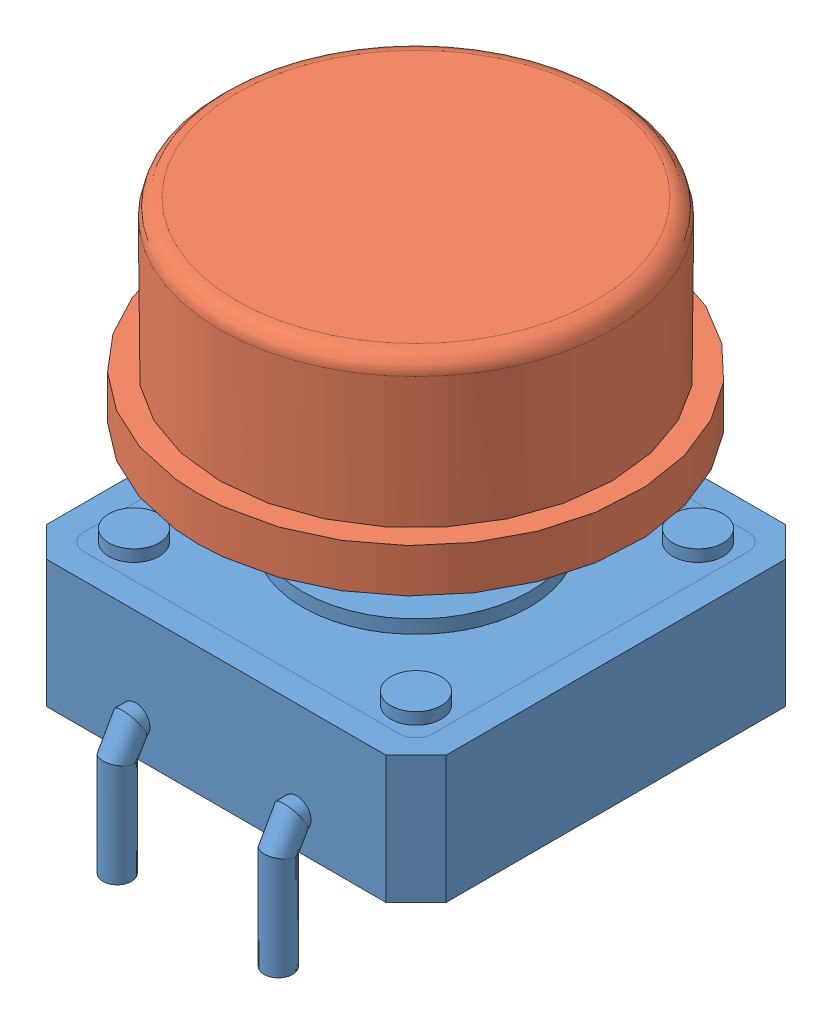
SolidWorks assembly Кнопка с колпачком, configuration По умолчанию. Lengths in mm.
Overall size (13 15.4 13.85).
2 component instances, 2 part files, 3 mates.
Components (placement in the parent):
- User Library-Button 12x12x7_3 - копия-1: User Library-Button 12x12x7_3 - копия [Default] at origin size (11.9 9.7 13.85)
- Колпачек13мм-1: Колпачек13мм [По умолчанию] at (0 7 0) size (13 7.7 13)
Mates (geometry in assembly coordinates):
- Параллельность1: parallel: plane of User Library-Button 12x12x7_3 - копия-1 through (0 7 0) normal (0 1 0); plane of Колпачек13мм-1 through (0.4818 7 0) normal (0 -1 0)
- Совпадение22: coincident: line of User Library-Button 12x12x7_3 - копия-1 through (1.8 7 -1.9) axis (-1 0 0); line of Колпачек13мм-1 through (-1.4182 7 -1.9) axis (1 0 0)
- Совпадение24: coincident: line of User Library-Button 12x12x7_3 - копия-1 through (1.9 7 1.8) axis (0 0 -1); line of Колпачек13мм-1 through (1.9 7 -1.9) axis (0 0 1)
